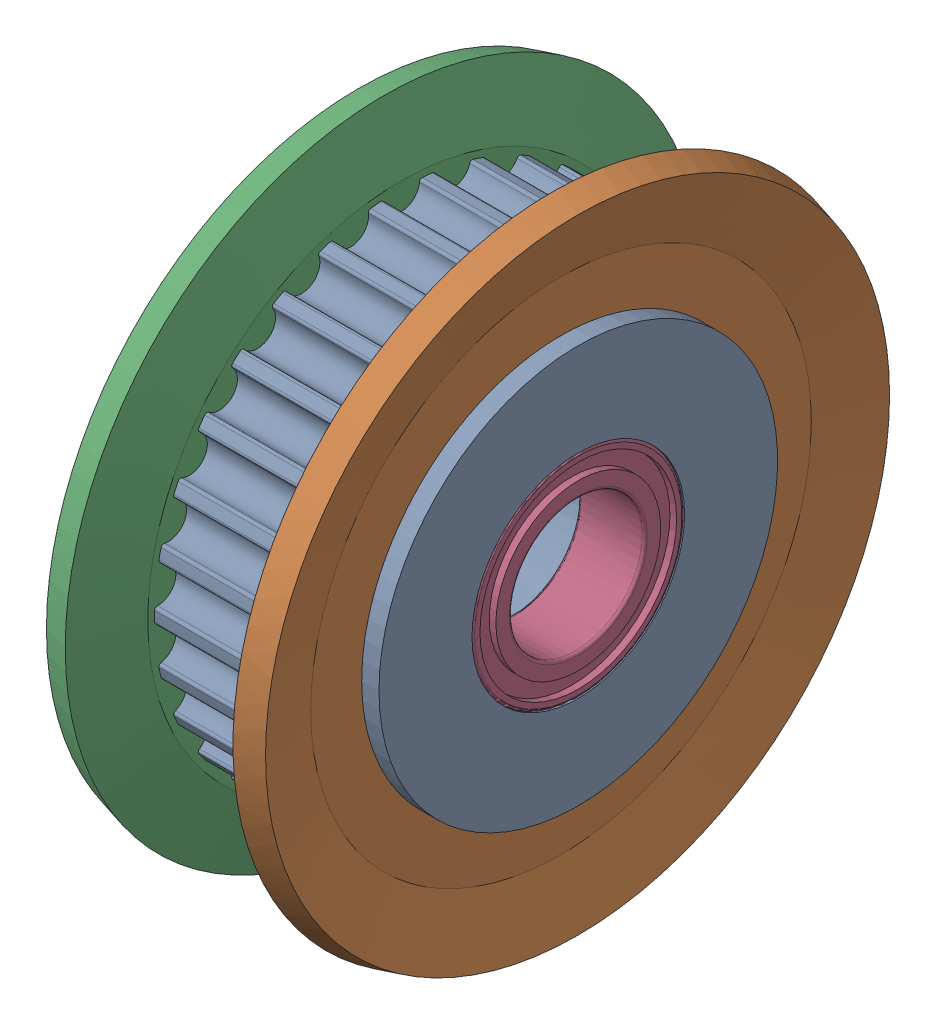
SolidWorks assembly Idler_AGTFW30-GT2040-5_MISUMI, configuration Default. Lengths in mm.
Overall size (8.3 24 24).
5 component instances, 3 part files, 10 mates.
Components (placement in the parent):
- Idler_Idler_AGTFW30-GT2040-5_MISUMI-1: Idler_Idler_AGTFW30-GT2040-5_MISUMI [Default] at origin size (8.3 18.52 18.59)
- Flange_Idler_AGTFW30-GT2040-5_MISUMI-1: Flange_Idler_AGTFW30-GT2040-5_MISUMI [Default] at (7.65 0 0) x (-1 0 0) z (0 0 -1) size (1.62 24 24)
- Flange_Idler_AGTFW30-GT2040-5_MISUMI-2: Flange_Idler_AGTFW30-GT2040-5_MISUMI [Default] at (0.65 0 0) size (1.62 24 24)
- Bearing_Idler_AGTFW30-GT2040-5_MISUMI-1: Bearing_Idler_AGTFW30-GT2040-5_MISUMI [Default] at (5.8 0 0) size (2.5 8 8)
- Bearing_Idler_AGTFW30-GT2040-5_MISUMI-2: Bearing_Idler_AGTFW30-GT2040-5_MISUMI [Default] at origin size (2.5 8 8)
Mates (geometry in assembly coordinates):
- Concentric1: concentric anti-aligned: cylinder of Idler_BaseModel20220427134436-1 through (0 0 0) axis (-1 0 0) radius 7.5; cylinder of Flange_BaseModel20220427134436-1 through (7.65 0 0) axis (1 0 0) radius 7.5
- Coincident1: coincident anti-aligned: plane of Idler_BaseModel20220427134436-1 through (6.65 7.5 0) normal (1 0 0); plane of Flange_BaseModel20220427134436-1 through (6.65 7.5 0) normal (-1 0 0)
- Concentric2: concentric aligned: cylinder of Idler_BaseModel20220427134436-1 through (0 0 0) axis (-1 0 0) radius 7.5; cylinder of Flange_BaseModel20220427134436-2 through (0.65 0 0) axis (-1 0 0) radius 7.5
- Coincident2: coincident anti-aligned: plane of Flange_BaseModel20220427134436-2 through (1.65 7.5 0) normal (1 0 0); plane of Idler_BaseModel20220427134436-1 through (1.65 9.295 0) normal (-1 0 0)
- Concentric3: concentric aligned: cylinder of Idler_BaseModel20220427134436-1 through (0 0 0) axis (-1 0 0) radius 4; cylinder of Bearing_BaseModel20220427134436-1 through (5.8 0 0) axis (-1 0 0) radius 4
- Coincident3: coincident anti-aligned: plane of Idler_BaseModel20220427134436-1 through (5.8 3.5 0) normal (1 0 0); plane of Bearing_BaseModel20220427134436-1 through (5.8 4 0) normal (-1 0 0)
- Concentric4: concentric aligned: cylinder of Idler_BaseModel20220427134436-1 through (0 0 0) axis (-1 0 0) radius 4; cylinder of Bearing_BaseModel20220427134436-2 through (0 0 0) axis (-1 0 0) radius 4
- Coincident4: coincident anti-aligned: plane of Idler_BaseModel20220427134436-1 through (2.5 4 0) normal (-1 0 0); plane of Bearing_BaseModel20220427134436-2 through (2.5 3.7 0) normal (1 0 0)
- Coincident5: coincident anti-aligned: plane of Idler_BaseModel20220427134436-1 through (0 0 0) normal (0 0 1); plane of Flange_BaseModel20220427134436-1 through (7.65 0 0) normal (0 0 -1)
- Coincident6: coincident aligned: plane of Idler_BaseModel20220427134436-1 through (0 0 0) normal (0 0 1); plane of Flange_BaseModel20220427134436-2 through (0.65 0 0) normal (0 0 1)
